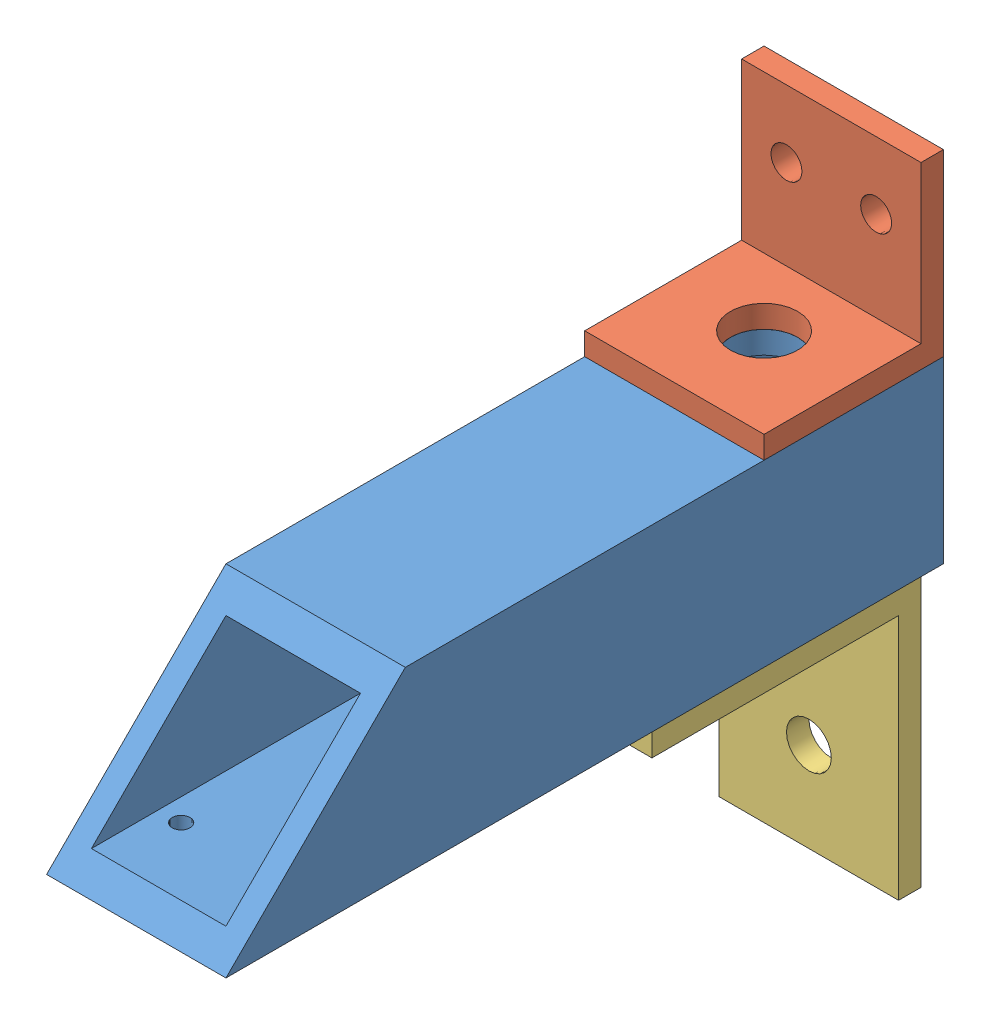
SolidWorks assembly bumper mount + bracket, configuration Default. Lengths in mm.
Overall size (25.4 88.9 101.6).
3 component instances, 3 part files, 5 mates.
Components (placement in the parent):
- bumper mount-1: bumper mount [Default] at origin size (25.4 25.4 101.6)
- bumpber bracket-1: bumpber bracket [Default] at (0 12.7 12.7) size (25.4 25.4 25.4)
- L Channel Bumper Mount-1: L Channel Bumper Mount [Default] at (-12.7 -12.7 3.175) x (0 0 1) z (1 0 0) size (38.1 38.1 25.4)
Mates (geometry in assembly coordinates):
- Coincident1: coincident aligned: circle of bumper mount-1; cylinder of bumpber bracket-1 through (0 12.7 12.7) axis (0 1 0) radius 4.7625
- Coincident2: coincident anti-aligned: plane of bumper mount-1 through (-12.7 12.7 101.6) normal (0 1 0); plane of bumpber bracket-1 through (0 12.7 12.7) normal (0 -1 0)
- Concentric1: concentric anti-aligned: cylinder of bumper mount-1 through (0 -12.7 12.7) axis (0 1 0) radius 4.7625; cylinder of L Channel Bumper Mount-1 through (0 -12.7 12.7) axis (0 -1 0) radius 4.7625
- Coincident3: coincident anti-aligned: plane of bumper mount-1 through (-12.7 -12.7 101.6) normal (0 -1 0); plane of L Channel Bumper Mount-1 through (12.7 -12.7 3.175) normal (0 1 0)
- Parallel1: parallel aligned: plane of bumper mount-1 through (0 0 0) normal (0 0 -1); plane of L Channel Bumper Mount-1 through (12.7 -12.7 3.175) normal (0 0 -1)
